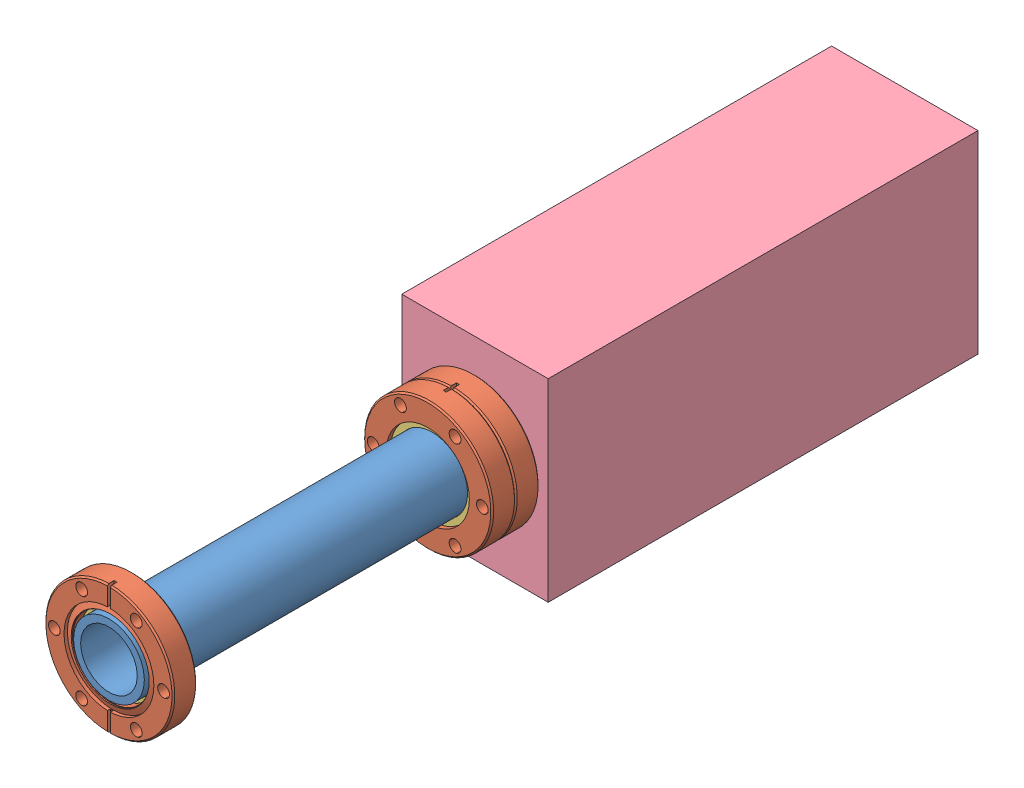
SolidWorks assembly RGA, configuration Default. Lengths in mm.
Overall size (78.74 104.14 427.99).
11 component instances, 4 part files, 11 mates.
Components (placement in the parent):
- RGAtube-1: RGAtube [Default] at (33.0848 37.2428 -42.7606) size (38.1 38.1 184.15)
- RGAflange-2: RGAflange [Default] at (41.9156 31.1626 135.0394) size (69.34 69.34 12.7)
  - 130094_1-1: 130094_1 [Default] at (-8.8308 6.0802 -6.35) size (69.34 69.34 12.7)
  - glass_1-1: glass_1 [Default] at (-8.8308 6.0802 1.0414) x (-1 0 0) z (0 0 -1) size (44.7 44.7 5.08)
- RGAflange-3: RGAflange [Default] at (24.254 31.1626 -36.4106) x (-1 0 0) z (0 0 -1) size (69.34 69.34 12.7)
  - 130094_1-1: 130094_1 [Default] at (-8.8308 6.0802 -6.35) size (69.34 69.34 12.7)
  - glass_1-1: glass_1 [Default] at (-8.8308 6.0802 1.0414) x (-1 0 0) z (0 0 -1) size (44.7 44.7 5.08)
- RGAflange-4: RGAflange [Default] at (41.9156 31.1626 -49.1106) size (69.34 69.34 12.7)
  - 130094_1-1: 130094_1 [Default] at (-8.8308 6.0802 -6.35) size (69.34 69.34 12.7)
  - glass_1-1: glass_1 [Default] at (-8.8308 6.0802 1.0414) x (-1 0 0) z (0 0 -1) size (44.7 44.7 5.08)
- RGAbox-1: RGAbox [Default] at (-6.2852 -14.8272 -286.6006) size (78.74 104.14 231.14)
Mates (geometry in assembly coordinates):
- Coincident3: coincident aligned: plane of RGAtube-1 through (33.0848 37.2428 141.3894) normal (0 0 1); plane of RGAflange-2/130094_1-1 through (33.0848 37.2428 141.3894) normal (0 0 1)
- Concentric3: concentric aligned: circle of RGAtube-1; circle of RGAflange-2/130094_1-1
- Coincident4: coincident aligned: plane of RGAtube-1 through (33.0848 37.2428 -42.7606) normal (0 0 -1); plane of RGAflange-3/130094_1-1 through (33.0848 37.2428 -42.7606) normal (0 0 -1)
- Concentric4: concentric anti-aligned: circle of RGAtube-1; circle of RGAflange-3/130094_1-1
- Concentric5: concentric anti-aligned: circle of RGAflange-2/130094_1-1; circle of RGAflange-3/130094_1-1
- Coincident6: coincident anti-aligned: plane of RGAflange-3/130094_1-1 through (33.0848 37.2428 -42.7606) normal (0 0 -1); plane of RGAflange-4/130094_1-1 through (33.0848 37.2428 -42.7606) normal (0 0 1)
- Concentric6: concentric anti-aligned: circle of RGAflange-3/130094_1-1; circle of RGAflange-4/130094_1-1
- Concentric7: concentric aligned: circle of RGAflange-2/130094_1-1; circle of RGAflange-4/130094_1-1
- Coincident9: coincident anti-aligned: plane of RGAflange-4/130094_1-1 through (33.0848 37.2428 -55.4606) normal (0 0 -1); plane of RGAbox-1 through (-6.2852 89.3128 -55.4606) normal (0 0 1)
- Concentric8: concentric anti-aligned: circle of RGAflange-2/130094_1-1; circle of RGAbox-1
- Parallel1: parallel aligned: plane of RGAflange-4/130094_1-1 through (33.8722 73.0075 -14.56) normal (-1 0 0); plane of RGAbox-1 through (-6.2852 -14.8272 -55.4606) normal (-1 0 0)
